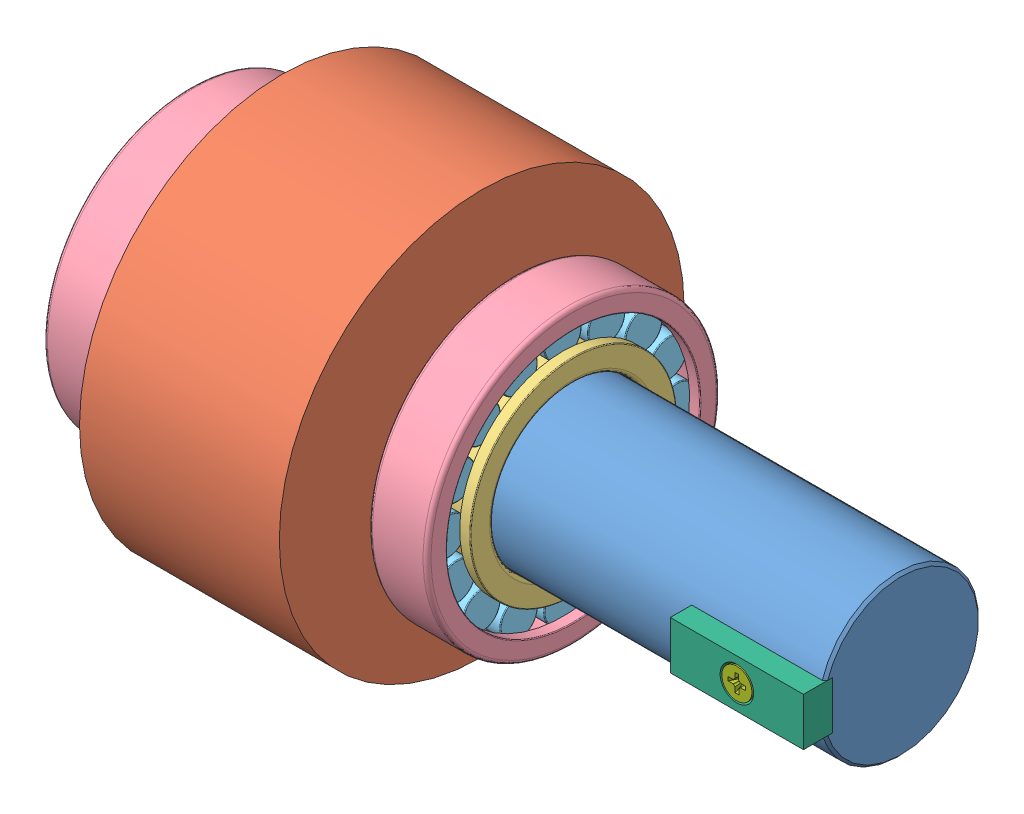
SolidWorks assembly podsklop_v2, configuration Default. Lengths in mm.
Overall size (286.33 152 152).
16 component instances, 9 part files, 20 mates.
Components (placement in the parent):
- vratilo_2-1: vratilo_2 [Default] at (-307.9854 30.4063 33.1505) x (1 0 0) z (0 -1 0) size (272 65 65)
- zupcanik_2-1: zupcanik_2 [Default] at (-193.4854 30.4063 33.1505) x (0 -1 0) z (-1 0 0) size (152 152 75)
- skf_bearing_nup_212_ecm_2-1: skf_bearing_nup_212_ecm_2 [Default] at (-180.9854 30.4063 33.1505) size (22 110 110)
  - skf_bearing_nup_212_ecm_2_01-1: skf_bearing_nup_212_ecm_2_01 [Default] at origin size (22 77.5 77.5)
  - skf_bearing_nup_212_ecm_2_02-1: skf_bearing_nup_212_ecm_2_02 [Default] at origin size (22 110 110)
  - skf_bearing_nup_212_ecm_2_03-1: skf_bearing_nup_212_ecm_2_03 [Default] at origin size (14 100 100)
- skf_bearing_nup_212_ecm_2-2: skf_bearing_nup_212_ecm_2 [Default] at (-302.9854 30.4063 33.1505) size (22 110 110)
  - skf_bearing_nup_212_ecm_2_01-1: skf_bearing_nup_212_ecm_2_01 [Default] at origin size (22 77.5 77.5)
  - skf_bearing_nup_212_ecm_2_02-1: skf_bearing_nup_212_ecm_2_02 [Default] at origin size (22 110 110)
  - skf_bearing_nup_212_ecm_2_03-1: skf_bearing_nup_212_ecm_2_03 [Default] at origin size (14 100 100)
- pero_zupcanika-1: pero_zupcanika [Default] at (-255.9854 30.4063 58.8505) x (1 0 0) z (0 -1 0) size (68 11 18)
- pero_zupcanika-2: pero_zupcanika [za_spojku2] at (-85.9854 30.4063 58.8505) x (1 0 0) z (0 -1 0) size (75.25 11 18)
- countersunk flat head cross recess screw_din-2: countersunk flat head cross recess screw_din [DIN EN ISO 7046-1 - M6 x 12 - Z - 12N] at (-60.9854 30.4063 69.8505) x (0 0 -1) z (0.999719 0.023723 0) size (12 11.3 11.3)
- circlip for shafts normal_din-2: circlip for shafts normal_din [Circlip DIN 471 - 60 x 2] at (-305.1354 30.4063 33.1505) x (0 0 1) z (-1 0 0) size (65.65 70.2 2)
- distantni_prsten-1: distantni_prsten [Default] at (-180.9854 30.4063 33.1505) x (0 1 0) z (0 0 1) size (70 12.5 70)
- distantni_prsten-2: distantni_prsten [Default] at (-268.4854 30.4063 33.1505) x (0 1 0) z (0 0 1) size (70 12.5 70)
Mates (geometry in assembly coordinates):
- Coincident1: coincident anti-aligned: plane of vratilo_2-1 through (-255.9854 21.4063 65.6515) normal (0 1 0); plane of pero_zupcanika-1 through (-255.9854 21.4063 69.8505) normal (0 -1 0)
- Coincident2: coincident anti-aligned: plane of vratilo_2-1 through (-255.9854 30.4063 58.8505) normal (0 0 1); plane of pero_zupcanika-1 through (-255.9854 30.4063 58.8505) normal (0 0 -1)
- Concentric1: concentric aligned: cylinder of vratilo_2-1 through (-205.9854 30.4063 65.6515) axis (0 0 -1) radius 9; cylinder of pero_zupcanika-1 through (-205.9854 30.4063 69.8505) axis (0 0 -1) radius 9
- Concentric2: concentric anti-aligned: circle of vratilo_2-1; circle of zupcanik_2-1
- Distance1: distance = 12.5 mm aligned: plane of zupcanik_2-1 through (-268.4854 30.4063 33.1505) normal (-1 0 0); plane of vratilo_2-1 through (-280.9854 30.4063 63.9432) normal (-1 0 0)
- Coincident5: coincident anti-aligned: plane of zupcanik_2-1 through (-268.4854 39.4063 64.3795) normal (0 -1 0); plane of pero_zupcanika-1 through (-255.9854 39.4063 69.8505) normal (0 1 0)
- Coincident8: coincident anti-aligned: plane of vratilo_2-1 through (-85.9854 21.4063 65.6515) normal (0 1 0); plane of pero_zupcanika-2 through (-85.9854 21.4063 69.8505) normal (0 -1 0)
- Coincident9: coincident anti-aligned: plane of vratilo_2-1 through (-307.9854 30.4063 58.8505) normal (0 0 1); plane of pero_zupcanika-2 through (-85.9854 30.4063 58.8505) normal (0 0 -1)
- Concentric3: concentric aligned: cylinder of vratilo_2-1 through (-60.9854 30.4063 58.8505) axis (0 0 1) radius 2.1; cylinder of pero_zupcanika-2 through (-60.9854 30.4063 69.8505) axis (0 0 1) radius 3.3
- Coincident10: coincident aligned: cone of pero_zupcanika-2 through (-60.9854 30.4063 69.8505) axis (0 0 -1); cone of countersunk flat head cross recess screw_din-2 through (-60.9854 30.4063 69.2005) axis (0 0 -1)
- Concentric4: concentric aligned: cylinder of vratilo_2-1 through (-307.9854 30.4063 33.1505) axis (-1 0 0) radius 30; cylinder of skf_bearing_nup_212_ecm_2-1/skf_bearing_nup_212_ecm_2_01-1 through (-169.9854 30.4063 33.1505) axis (-1 0 0) radius 30
- Coincident11: coincident anti-aligned: plane of vratilo_2-1 through (-180.9854 30.4063 65.6505) normal (1 0 0); plane of skf_bearing_nup_212_ecm_2-1/skf_bearing_nup_212_ecm_2_01-1 through (-180.9854 65.3813 33.1505) normal (-1 0 0)
- Concentric5: concentric aligned: cylinder of vratilo_2-1 through (-307.9854 30.4063 33.1505) axis (-1 0 0) radius 30; cylinder of skf_bearing_nup_212_ecm_2-2/skf_bearing_nup_212_ecm_2_01-1 through (-291.9854 30.4063 33.1505) axis (-1 0 0) radius 30
- Coincident12: coincident anti-aligned: plane of vratilo_2-1 through (-280.9854 30.4063 63.9432) normal (-1 0 0); plane of skf_bearing_nup_212_ecm_2-2/skf_bearing_nup_212_ecm_2_01-1 through (-280.9854 65.3813 33.1505) normal (1 0 0)
- Concentric6: concentric aligned: cylinder of vratilo_2-1 through (-307.9854 30.4063 33.1505) axis (-1 0 0) radius 30; cylinder of circlip for shafts normal_din-2 through (-303.1354 30.4063 33.1505) axis (-1 0 0) radius 28.5
- Coincident13: coincident anti-aligned: plane of vratilo_2-1 through (-305.1354 30.4063 63.1505) normal (1 0 0); plane of circlip for shafts normal_din-2 through (-305.1354 30.4063 33.1505) normal (-1 0 0)
- Concentric7: concentric anti-aligned: cylinder of vratilo_2-1 through (-307.9854 30.4063 33.1505) axis (-1 0 0) radius 30; cylinder of distantni_prsten-1 through (-193.4854 30.4063 33.1505) axis (1 0 0) radius 32.5
- Coincident14: coincident anti-aligned: plane of zupcanik_2-1 through (-193.4854 30.4063 33.1505) normal (1 0 0); plane of distantni_prsten-1 through (-193.4854 30.4063 33.1505) normal (-1 0 0)
- Concentric8: concentric anti-aligned: cylinder of vratilo_2-1 through (-307.9854 30.4063 33.1505) axis (-1 0 0) radius 30; cylinder of distantni_prsten-2 through (-280.9854 30.4063 33.1505) axis (1 0 0) radius 32.5
- Coincident15: coincident anti-aligned: plane of zupcanik_2-1 through (-268.4854 30.4063 33.1505) normal (-1 0 0); plane of distantni_prsten-2 through (-268.4854 30.4063 33.1505) normal (1 0 0)
